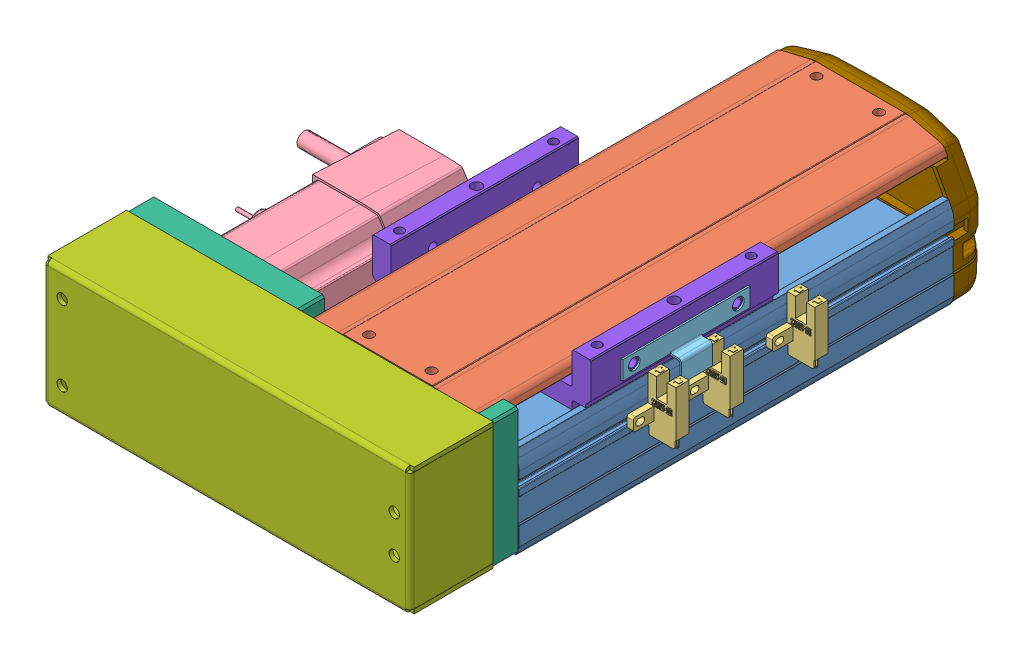
SolidWorks assembly S10-BR-100W, configuration 默认. Lengths in mm.
Overall size (206.39 66.8 282.24).
11 component instances, 9 part files, 35 mates.
Components (placement in the parent):
- S10-BR底座^S10-BR-100W-1: S10-BR底座^S10-BR-100W [默认] at (-105.9271 -5.9237 -417.9615) size (102 43 221) (virtual)
- S10-BR上盖^S10-BR-100W-1: S10-BR上盖^S10-BR-100W [默认] at (-105.9271 53.5763 -298.3615) size (83.88 8 227) (virtual)
- EE-SX672 传感器^S10-BR-100W-1: EE-SX672 传感器^S10-BR-100W [默认] at (-48.1771 28.1763 -325.5615) x (1 0 0) z (0 0 -1) size (13.5 27.4 26.1) (virtual)
- 复件 M10^S10-BR-100W-1: 复件 M10^S10-BR-100W [默认] at (-189.1171 25.5763 -252.9615) x (0 1 0) z (0 0 -1) size (42.1 79.78 121.76) (virtual)
- S10-GY外置感应钢片^S10-BR-100W-1: S10-GY外置感应钢片^S10-BR-100W [默认] at (-53.0271 54.5763 -274.9615) size (6 19 61) (virtual)
- EE-SX672 传感器^S10-BR-100W-2: EE-SX672 传感器^S10-BR-100W [默认] at (-48.1771 28.1763 -284.8615) x (1 0 0) z (0 0 -1) size (13.5 27.4 26.1) (virtual)
- EE-SX672 传感器^S10-BR-100W-3: EE-SX672 传感器^S10-BR-100W [默认] at (-48.1771 28.1763 -258.7615) x (1 0 0) z (0 0 -1) size (13.5 27.4 26.1) (virtual)
- S10-BL-P10电机左折板^S10-BR-100W-1: S10-BL-P10电机左折板^S10-BR-100W [Default] at (-1234.7619 -789.214 -190.9615) x (1 0 0) z (0 -1 0) size (176 12 61) (virtual)
- S10-BL盖子^S10-BR-100W-1: S10-BL盖子^S10-BR-100W [默认] at (-229.4271 -5.9237 -144.9615) size (176 61.01 40.01) (virtual)
- S10-BC滑座^S10-BR-100W-1: S10-BC滑座^S10-BR-100W [默认] at (-124.4271 24.5763 -274.9615) size (105 52.5 90) (virtual)
- 复件 S10端盖^S10-BR-100W-1: 复件 S10端盖^S10-BR-100W [Default] at (-105.9268 -7.1147 14.1385) size (104.96 63.3 21.34) (virtual)
Mates (geometry in assembly coordinates):
- 距离2: distance = 62.5 mm: plane of S10-BR上盖^S10-BR-100W-1 through (-127.2363 55.5763 -184.8615) normal (0 1 0); plane of S10-BR底座^S10-BR-100W-1 through (-105.9271 -6.9237 -417.9615) normal (0 -1 0)
- 重合31: coincident: plane of S10-BR底座^S10-BR-100W-1 through (-105.9271 -5.9237 -417.9615) normal (1 0 0); plane of S10-BR上盖^S10-BR-100W-1 through (-105.9271 53.5763 -298.3615) normal (1 0 0)
- 距离3: distance = 66 mm: plane of S10-BC滑座^S10-BR-100W-1 through (-176.0667 59.0763 -345.7188) normal (0 1 0); plane of S10-BR底座^S10-BR-100W-1 through (-105.9271 -6.9237 -417.9615) normal (0 -1 0)
- 距离5: distance = 1.5 mm: plane of S10-BC滑座^S10-BR-100W-1 through (-53.4271 39.1592 -229.9615) normal (1 0 0); plane of S10-BR底座^S10-BR-100W-1 through (-54.9271 -2.8683 -196.9615) normal (1 0 0)
- 距离8: distance = 24 mm: plane of S10-BR底座^S10-BR-100W-1 through (-105.9271 -6.9237 -417.9615) normal (0 -1 0); plane of EE-SX672 传感器^S10-BR-100W-1 through (-54.9271 17.0763 -331.8615) normal (0 -1 0)
- 重合65: coincident: plane of S10-BR底座^S10-BR-100W-1 through (-54.9271 18.1587 -196.9615) normal (1 0 0); plane of EE-SX672 传感器^S10-BR-100W-1 through (-54.9271 39.2763 -331.8615) normal (-1 0 0)
- 重合43: coincident: plane of S10-BC滑座^S10-BR-100W-1 through (-53.4271 39.1592 -229.9615) normal (1 0 0); plane of S10-GY外置感应钢片^S10-BR-100W-1 through (-53.4271 52.5763 -305.4615) normal (-1 0 0)
- 同心16: concentric: cylinder of S10-BC滑座^S10-BR-100W-1 through (-53.4271 44.2785 -249.9615) axis (1 0 0) radius 2.1; cylinder of S10-GY外置感应钢片^S10-BR-100W-1 through (-53.4271 44.2785 -246.1615) axis (-1 0 0) radius 2.8
- 同心17: concentric: cylinder of S10-BC滑座^S10-BR-100W-1 through (-53.4271 44.2785 -299.9615) axis (1 0 0) radius 2.1; cylinder of S10-GY外置感应钢片^S10-BR-100W-1 through (-53.4271 44.2785 -296.1615) axis (-1 0 0) radius 2.8
- 重合51: coincident: plane of EE-SX672 传感器^S10-BR-100W-1 through (-54.9271 39.2763 -331.8615) normal (0 1 0); plane of EE-SX672 传感器^S10-BR-100W-2 through (-54.9271 39.2763 -291.1615) normal (0 1 0)
- 重合52: coincident: plane of EE-SX672 传感器^S10-BR-100W-1 through (-54.9271 39.2763 -331.8615) normal (0 1 0); plane of EE-SX672 传感器^S10-BR-100W-3 through (-54.9271 39.2763 -265.0615) normal (0 1 0)
- 重合56: coincident: plane of S10-BR底座^S10-BR-100W-1 through (-151.5313 35.8763 -196.9615) normal (0 0 1); plane of S10-BL-P10电机左折板^S10-BR-100W-1 through (-1234.7619 -789.214 -196.9615) normal (0 0 -1)
- 重合57: coincident: plane of S10-BR底座^S10-BR-100W-1 through (-130.4272 -5.9237 -196.9615) normal (0 -1 0); plane of S10-BL-P10电机左折板^S10-BR-100W-1 through (-68.8655 -5.9237 -184.9615) normal (0 -1 0)
- 重合58: coincident: plane of S10-BR底座^S10-BR-100W-1 through (-55.4271 6.6587 -196.9615) normal (1 0 0); plane of S10-BL-P10电机左折板^S10-BR-100W-1 through (-55.4271 32.818 -184.9615) normal (1 0 0)
- 重合59: coincident: plane of S10-BL-P10电机左折板^S10-BR-100W-1 through (-1234.7619 -789.214 -184.9615) normal (0 0 1); plane of S10-BL盖子^S10-BR-100W-1 through (-55.4271 52.9763 -184.9615) normal (0 0 -1)
- 重合60: coincident: plane of S10-BL-P10电机左折板^S10-BR-100W-1 through (-55.4271 32.818 -184.9615) normal (1 0 0); plane of S10-BL盖子^S10-BR-100W-1 through (-55.4271 -3.8237 -146.9615) normal (1 0 0)
- 重合61: coincident: plane of S10-BL-P10电机左折板^S10-BR-100W-1 through (-68.8655 -5.9237 -184.9615) normal (0 -1 0); plane of S10-BL盖子^S10-BR-100W-1 through (-229.4271 -5.9237 -146.9615) normal (0 -1 0)
- 重合62: coincident: plane of 复件 M10^S10-BR-100W-1 through (-190.6149 103.5748 -196.9615) normal (0 0 1); plane of S10-BL-P10电机左折板^S10-BR-100W-1 through (-1234.7619 -789.214 -196.9615) normal (0 0 -1)
- 平行2: parallel: plane of 复件 M10^S10-BR-100W-1 through (-209.1171 25.5763 -252.9615) normal (-1 0 0); plane of S10-BL-P10电机左折板^S10-BR-100W-1 through (-231.4271 54.0763 -184.9615) normal (-1 0 0)
- 重合63: coincident: plane of EE-SX672 传感器^S10-BR-100W-1 through (-54.9271 39.2763 -331.8615) normal (-1 0 0); plane of EE-SX672 传感器^S10-BR-100W-3 through (-54.9271 39.2763 -265.0615) normal (-1 0 0)
- 重合64: coincident: plane of EE-SX672 传感器^S10-BR-100W-2 through (-54.9271 39.2763 -291.1615) normal (-1 0 0); plane of EE-SX672 传感器^S10-BR-100W-3 through (-54.9271 39.2763 -265.0615) normal (-1 0 0)
- 重合66: coincident: plane of EE-SX672 传感器^S10-BR-100W-2 through (-51.9271 20.2763 -274.9615) normal (0 0 1); plane of EE-SX672 传感器^S10-BR-100W-3 through (-51.9271 20.2763 -274.9615) normal (0 0 -1)
- 重合67: coincident: plane of S10-BR上盖^S10-BR-100W-1 through (-145.8568 47.7763 -411.8615) normal (0 0 -1); plane of 复件 S10端盖^S10-BR-100W-1 through (-55.9268 46.3853 -411.8615) normal (0 0 1)
- 重合69: coincident: line of S10-BR底座^S10-BR-100W-1 through (-55.4271 6.6587 -405.8615) axis (0 1 0); line of 复件 S10端盖^S10-BR-100W-1 through (-55.4271 17.775 -405.8615) axis (0 -1 0)
- 重合70: coincident: line of S10-BR上盖^S10-BR-100W-1 through (-84.6179 55.5763 -411.8615) axis (-1 0 0); line of 复件 S10端盖^S10-BR-100W-1 through (-83.9637 55.5763 -411.8615) axis (-1 0 0)
- 宽度1: width: plane of EE-SX672 传感器^S10-BR-100W-3 through (-41.4271 17.0763 -261.2615) normal (0 0 -1); plane of EE-SX672 传感器^S10-BR-100W-2 through (-41.4271 17.0763 -281.0615) normal (0 0 1); plane of S10-GY外置感应钢片^S10-BR-100W-1 through (-52.6271 39.7785 -263.6615) normal (0 0 1); plane of S10-GY外置感应钢片^S10-BR-100W-1 through (-52.6271 39.7785 -278.6615) normal (0 0 -1)
- 距离12: distance = 110 mm: plane of EE-SX672 传感器^S10-BR-100W-3 through (-41.4271 17.0763 -258.7615) normal (0 0 1); plane of S10-BL盖子^S10-BR-100W-1 through (-57.4271 55.0763 -144.9615) normal (0 0 1)
- 距离13: distance = 74 mm: plane of S10-BR底座^S10-BR-100W-1 through (-59.1771 36.0763 -405.8615) normal (0 0 -1); plane of EE-SX672 传感器^S10-BR-100W-1 through (-41.4271 17.0763 -331.8615) normal (0 0 -1)
- 距离15: distance = 32.19 mm: cylinder of 复件 M10^S10-BR-100W-1 through (-189.1171 25.5763 -171.9615) axis (0 0 -1) radius 4; plane of S10-BR底座^S10-BR-100W-1 through (-156.9271 5.993 -196.9615) normal (-1 0 0)
- 距离16: distance = 32.5 mm: cylinder of 复件 M10^S10-BR-100W-1 through (-189.1171 25.5763 -171.9615) axis (0 0 -1) radius 4; plane of S10-BR底座^S10-BR-100W-1 through (-105.9271 -6.9237 -417.9615) normal (0 -1 0)
- 距离17: distance = 130 mm: plane of S10-BL盖子^S10-BR-100W-1 through (-57.4271 55.0763 -144.9615) normal (0 0 1); cylinder of S10-BC滑座^S10-BR-100W-1 through (-58.4271 47.0763 -274.9615) axis (0 1 0) radius 2.5
- 同心18: concentric: cylinder of S10-GY外置感应钢片^S10-BR-100W-1 through (-53.4271 48.0763 -249.9615) axis (-1 0 0) radius 2.8; cylinder of S10-BC滑座^S10-BR-100W-1 through (-53.4271 48.0763 -249.9615) axis (1 0 0) radius 2.1
- 同心19: concentric: cylinder of S10-GY外置感应钢片^S10-BR-100W-1 through (-53.4271 48.0763 -299.9615) axis (-1 0 0) radius 2.8; cylinder of S10-BC滑座^S10-BR-100W-1 through (-53.4271 48.0763 -299.9615) axis (1 0 0) radius 2.1
- 宽度2: width: plane of EE-SX672 传感器^S10-BR-100W-2 through (-41.4271 17.0763 -284.8615) normal (0 0 1); plane of EE-SX672 传感器^S10-BR-100W-3 through (-41.4271 17.0763 -265.0615) normal (0 0 -1); plane of S10-GY外置感应钢片^S10-BR-100W-1 through (-52.6271 43.5763 -267.4615) normal (0 0 1); plane of S10-GY外置感应钢片^S10-BR-100W-1 through (-52.6271 43.5763 -282.4615) normal (0 0 -1)
- 距离18: distance = 66 mm: plane of S10-BC滑座^S10-BR-100W-1 through (-176.0667 59.0763 -345.7188) normal (0 1 0); plane of S10-BR底座^S10-BR-100W-1 through (-105.9271 -6.9237 -417.9615) normal (0 -1 0)
